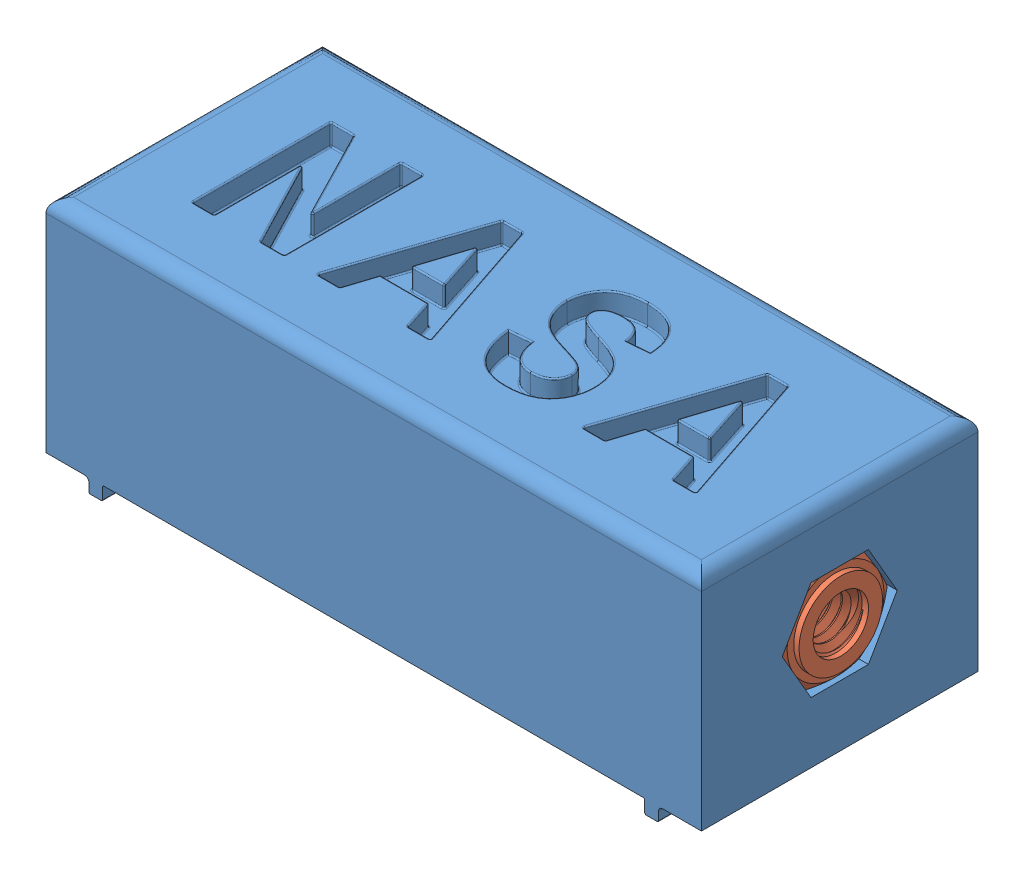
SolidWorks assembly Support_Block_Assembly, configuration Default. Lengths in mm.
Overall size (47.56 17.11 20).
3 component instances, 2 part files, 6 mates.
Components (placement in the parent):
- Support_Block_P-1: Support_Block_P [Default] at (17.1001 15.2266 38.025) size (47.4 17.11 20)
- M4 x 0.7 Hex Nut-1: M4 x 0.7 Hex Nut [90592A090] at (-4.6999 23.2266 38.025) x (0 -0.5 -0.866025) z (0 0.866025 -0.5) size (7 3.86 8.08)
- M4 x 0.7 Hex Nut-2: M4 x 0.7 Hex Nut [90592A090] at (38.9001 23.2266 38.025) x (0 -1 0) z (0 0 1) size (7 3.86 8.08)
Mates (geometry in assembly coordinates):
- Coincident1: coincident: plane of Support_Block_P-1 through (37.3001 15.2266 38.025) normal (1 0 0); plane of M4 x 0.7 Hex Nut-2 through (37.3001 26.7266 36.0043) normal (-1 0 0)
- Concentric3: concentric: circle of Support_Block_P-1; circle of M4 x 0.7 Hex Nut-2
- Coincident2: coincident: plane of Support_Block_P-1 through (-3.0999 15.2266 38.025) normal (-1 0 0); plane of M4 x 0.7 Hex Nut-1 through (-3.0999 23.2266 42.0665) normal (1 0 0)
- Concentric4: concentric: circle of Support_Block_P-1; circle of M4 x 0.7 Hex Nut-1
- Parallel1: parallel anti-aligned: plane of Support_Block_P-1 through (-3.0999 23.2266 33.8681) normal (0 0.5 0.866025); plane of M4 x 0.7 Hex Nut-1 through (-6.2999 23.2266 33.9836) normal (0 -0.5 -0.866025)
- Parallel2: parallel anti-aligned: plane of Support_Block_P-1 through (37.3001 26.8266 40.1035) normal (0 -1 0); plane of M4 x 0.7 Hex Nut-2 through (40.5001 26.7266 36.0043) normal (0 1 0)
